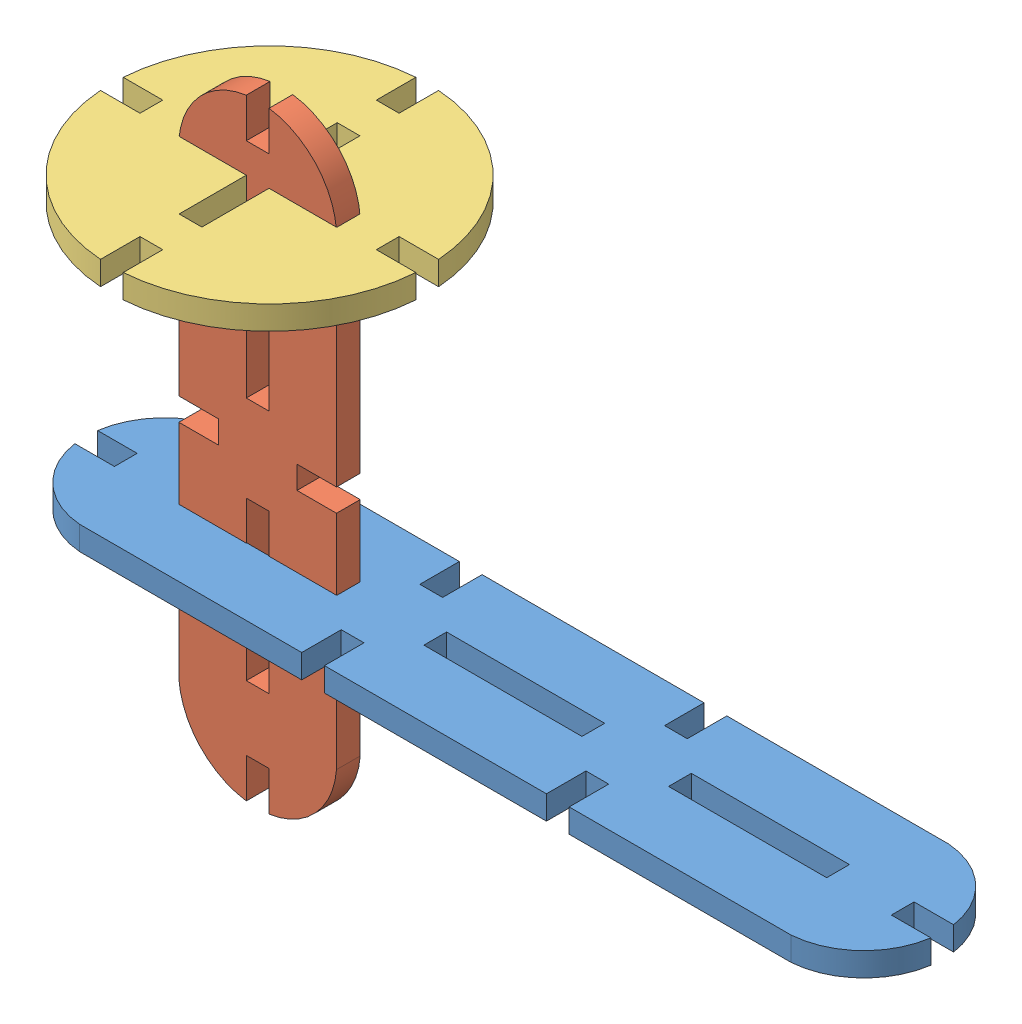
SolidWorks assembly Constructionkit, configuration Predeterminado. Lengths in mm.
Overall size (108.28 77.33 39.9).
3 component instances, 3 part files, 4 mates.
Components (placement in the parent):
- Making-1: Making [Predeterminado] at (0.9159 -2.3752 128.3122) size (108.28 3 19.94)
- Making1-1: Making1 [Predeterminado] at (-55.0696 31.5236 109.7837) x (0 1 0) z (-1 0 0) size (77.33 3 19.94)
- MakingA-1: MakingA [Predeterminado] at (-35.0411 37.9434 108.2837) size (39.9 3 39.9)
Mates (geometry in assembly coordinates):
- Width3: width anti-aligned: plane of Making1-1 through (-25.0696 -18.4764 106.7837) normal (1 0 0); plane of Making1-1 through (-45.0126 -18.4764 106.7837) normal (-1 0 0); plane of Making-1 through (-25.0411 -2.3762 109.7222) normal (-1 0 0); plane of Making-1 through (-45.0411 -2.3762 109.7222) normal (1 0 0)
- Width4: width anti-aligned: plane of Making1-1 through (-35.0411 39.8185 109.7837) normal (0 0 1); plane of Making1-1 through (-35.0411 39.8185 106.7837) normal (0 0 -1); plane of Making-1 through (-45.0411 -2.3762 109.7222) normal (0 0 -1); plane of Making-1 through (-45.0411 -2.3762 106.8452) normal (0 0 1)
- Width5: width anti-aligned: plane of MakingA-1 through (-45.0411 37.9424 106.8452) normal (0 0 1); plane of MakingA-1 through (-45.0411 37.9424 109.7222) normal (0 0 -1); plane of Making1-1 through (-35.0411 39.8185 106.7837) normal (0 0 -1); plane of Making1-1 through (-35.0411 39.8185 109.7837) normal (0 0 1)
- Width6: width anti-aligned: plane of Making1-1 through (-25.0696 40.5726 106.7837) normal (1 0 0); plane of Making1-1 through (-45.0126 40.5726 106.7837) normal (-1 0 0); plane of MakingA-1 through (-25.0411 37.9424 109.7222) normal (-1 0 0); plane of MakingA-1 through (-45.0411 37.9424 109.7222) normal (1 0 0)
